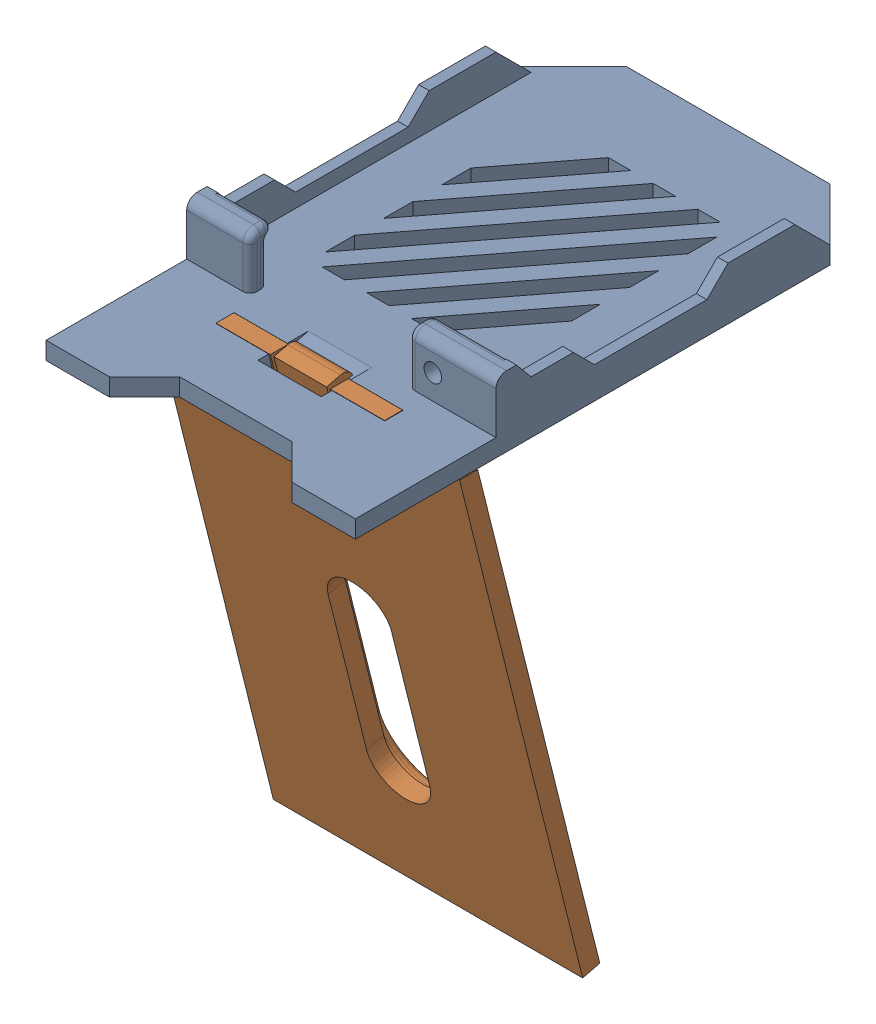
SolidWorks assembly Phone_Stand_Assem1, configuration Default. Lengths in mm.
Overall size (88 160.47 150).
2 component instances, 2 part files, 0 mates.
Components (placement in the parent):
- Phone_Stand_Part1-1: Phone_Stand_Part1 [Default] at origin size (88 20 150)
- Phone_Stand_Part2-2: Phone_Stand_Part2 [Default] at (43.997 -140.4663 -64.6709) x (-1 0 0) z (0 0.242399 -0.970177) size (88 150 10)
